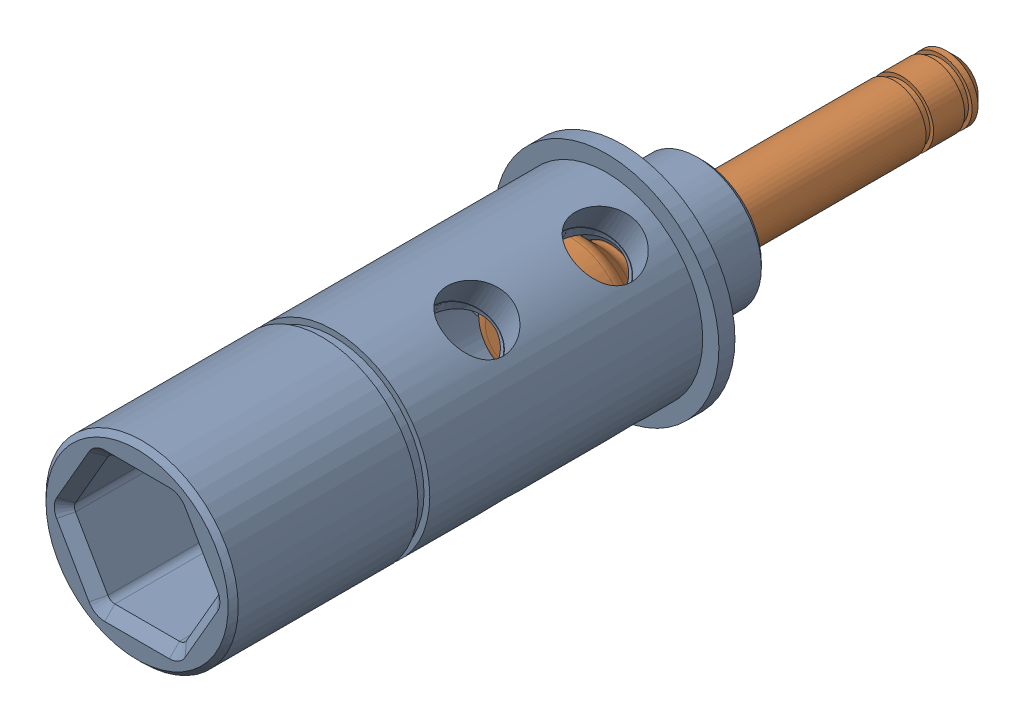
SolidWorks assembly 217-2790-001 Rev1, configuration Default. Lengths in mm.
Overall size (22.23 22.23 81.07).
2 component instances, 2 part files, 0 mates.
Components (placement in the parent):
- 217-2790-003 Rev1-1: 217-2790-003 Rev1 [Default] at origin size (22.23 22.23 55.94)
- 217-2790-004 Rev1-1: 217-2790-004 Rev1 [Default] at (0 0 14.3911) x (0.928141 0.372229 0) z (0 0 1) size (11.68 11.68 44.12)
